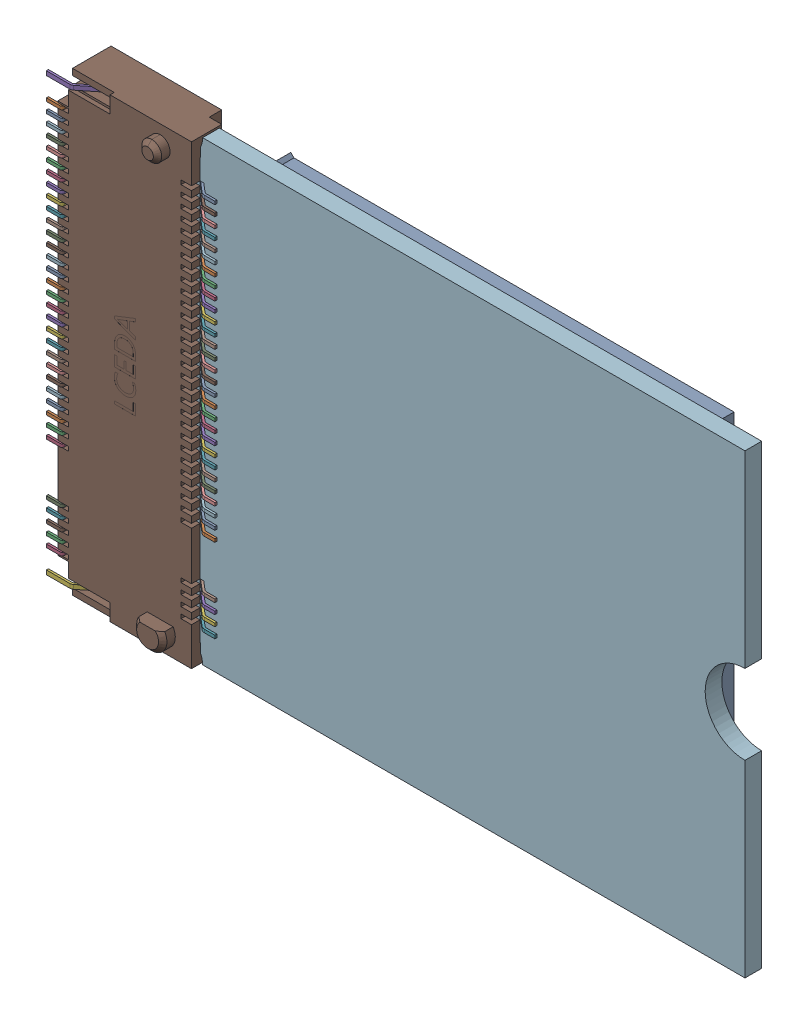
SolidWorks assembly CN2, configuration Défaut. Lengths in mm.
Overall size (32.96 21.86 3.04).
7 component instances, 3 part files, 0 mates.
Components (placement in the parent):
- APCI0146-P001A-1: APCI0146-P001A [Défaut] at (31.1734 -10.9968 -0.5418) x (0 -1 0) z (0 0 -1) size (21.85 8.07 2.65)
- m.2 SSD 2230-1: m.2 SSD 2230 [Défaut] at (-10.663 -62.5644 -3.3818) x (0 1 0) z (0 0 -1) size (21.86 29.97 2)
  - Board_1174-1: Board_1174 [Défaut] at origin size (21.86 29.97 0.8)
    - Open CASCADE STEP translator 7.5 3.1.1-1: Open CASCADE STEP translator 7.5 3.1.1 [Défaut] at (0 0 -0.8) size (21.86 29.97 0.8)
  - Free-Models-1: Free-Models [Défaut] at origin size (20.72 21.22 1.2)
    - 13909094304-1: 13909094304 [Défaut] at (51.6338 57.7291 0) size (20.72 21.22 1.2)
      - Extruded_1180-1: Extruded_1180 [Défaut] at origin size (20.72 21.22 1.2)
